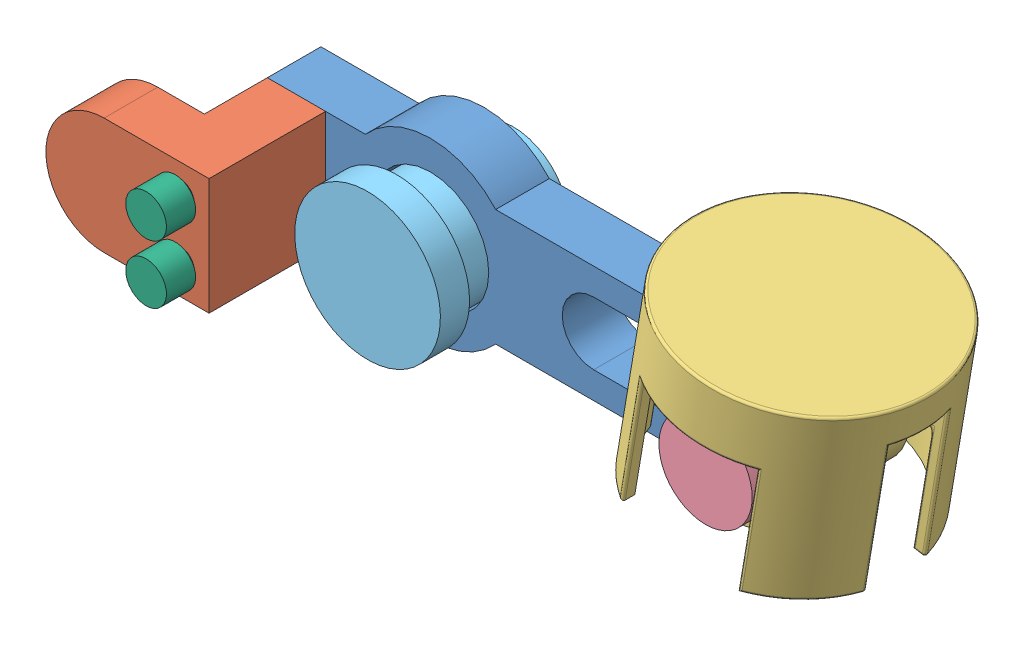
SolidWorks assembly Marble Reloading System V2, configuration Default. Lengths in mm.
Overall size (80.82 25.23 32).
7 component instances, 6 part files, 13 mates.
Components (placement in the parent):
- Stepper Arm V2 Right side-1: Stepper Arm V2 Right side [Default] at (32.1437 38.0128 41.8132) size (60.96 19.05 5.84)
- Stepper Arm V2 Left Side-1: Stepper Arm V2 Left Side [Default] at (8.0137 38.0128 47.6552) size (17.78 12.7 12.7)
- Basket Receiver for Stepper-1: Basket Receiver for Stepper [Default] at (60.4018 43.6478 44.9882) x (-0.985994 0.166782 0) z (0 0 -1) size (25.91 19.07 25.91)
- Small Pin for Marble Recapture-1: Small Pin for Marble Recapture [Default] at (59.4487 38.0128 51.3382) x (0.768857 0.63942 0) z (0 0 -1) size (10.16 10.16 15.88)
- Big Pin for Marble Recapture-1: Big Pin for Marble Recapture [Default] at (22.6187 38.0128 51.3382) x (-0.772551 -0.634953 0) z (0 0 -1) size (15.88 15.88 15.88)
- Stepper Arm V2 Pin-1: Stepper Arm V2 Pin [Default] at (8.0137 41.1878 41.8132) size (4.45 4.45 22.23)
- Stepper Arm V2 Pin-2: Stepper Arm V2 Pin [Default] at (8.0137 34.8378 41.8132) x (0.987351 0.158553 0) z (0 0 1) size (4.45 4.45 22.23)
Mates (geometry in assembly coordinates):
- Concentric1: concentric anti-aligned: cylinder of Stepper Arm V2 Right side-1 through (8.0137 41.1878 41.8132) axis (0 0 1) radius 1.5875; cylinder of Stepper Arm V2 Left Side-1 through (8.0137 41.1878 65.3533) axis (0 0 -1) radius 1.5875
- Concentric2: concentric anti-aligned: cylinder of Stepper Arm V2 Right side-1 through (8.0137 34.8378 41.8132) axis (0 0 1) radius 1.5875; cylinder of Stepper Arm V2 Left Side-1 through (8.0137 34.8378 65.3533) axis (0 0 -1) radius 1.5875
- Coincident1: coincident anti-aligned: plane of Stepper Arm V2 Right side-1 through (22.6187 38.0128 47.6552) normal (0 0 1); plane of Stepper Arm V2 Left Side-1 through (8.0137 38.0128 47.6552) normal (0 0 -1)
- Concentric3: concentric aligned: cylinder of Basket Receiver for Stepper-1 through (59.4487 38.0128 38.6382) axis (0 0 1) radius 3.175; cylinder of Small Pin for Marble Recapture-1 through (59.4487 38.0128 38.6382) axis (0 0 1) radius 2.925
- Concentric4: concentric anti-aligned: cylinder of Stepper Arm V2 Right side-1 through (22.6187 38.0128 48.1632) axis (0 0 -1) radius 6.35; cylinder of Big Pin for Marble Recapture-1 through (22.6187 38.0128 38.6382) axis (0 0 1) radius 6.1
- Concentric5: concentric anti-aligned: cylinder of Stepper Arm V2 Right side-1 through (8.0137 41.1878 41.8132) axis (0 0 1) radius 1.5875; cylinder of Stepper Arm V2 Pin-1 through (8.0137 41.1878 60.8632) axis (0 0 -1) radius 1.3375
- Coincident4: coincident aligned: plane of Stepper Arm V2 Right side-1 through (22.6187 38.0128 41.8132) normal (0 0 -1); plane of Stepper Arm V2 Pin-1 through (8.0137 41.1878 41.8132) normal (0 0 -1)
- Concentric6: concentric anti-aligned: cylinder of Stepper Arm V2 Right side-1 through (8.0137 34.8378 41.8132) axis (0 0 1) radius 1.5875; cylinder of Stepper Arm V2 Pin-2 through (8.0137 34.8378 60.8632) axis (0 0 -1) radius 1.3375
- Coincident5: coincident aligned: plane of Stepper Arm V2 Right side-1 through (22.6187 38.0128 41.8132) normal (0 0 -1); plane of Stepper Arm V2 Pin-2 through (8.0137 34.8378 41.8132) normal (0 0 -1)
- Distance3: distance = 3.175 mm aligned: plane of Big Pin for Marble Recapture-1 through (22.6187 38.0128 38.6382) normal (0 0 -1); plane of Stepper Arm V2 Right side-1 through (22.6187 38.0128 41.8132) normal (0 0 -1)
- Coincident9: coincident aligned: plane of Basket Receiver for Stepper-1 through (59.4487 38.0128 38.6382) normal (0 0 -1); plane of Small Pin for Marble Recapture-1 through (59.4487 38.0128 38.6382) normal (0 0 -1)
- Slot1: slot anti-aligned: cylinder of Basket Receiver for Stepper-1 through (59.4487 38.0128 51.3382) axis (0 0 -1) radius 3.175; plane of Stepper Arm V2 Right side-1 through (40.3987 34.5838 41.8122) normal (0 1 0); cylinder of Stepper Arm V2 Right side-1 through (40.3987 38.0128 41.8122) axis (0 0 1) radius 3.429
- Coincident10: coincident anti-aligned: plane of Stepper Arm V2 Right side-1 through (22.6187 38.0128 41.8132) normal (0 0 -1); plane of Basket Receiver for Stepper-1 through (59.4487 38.0128 41.8132) normal (0 0 1)
